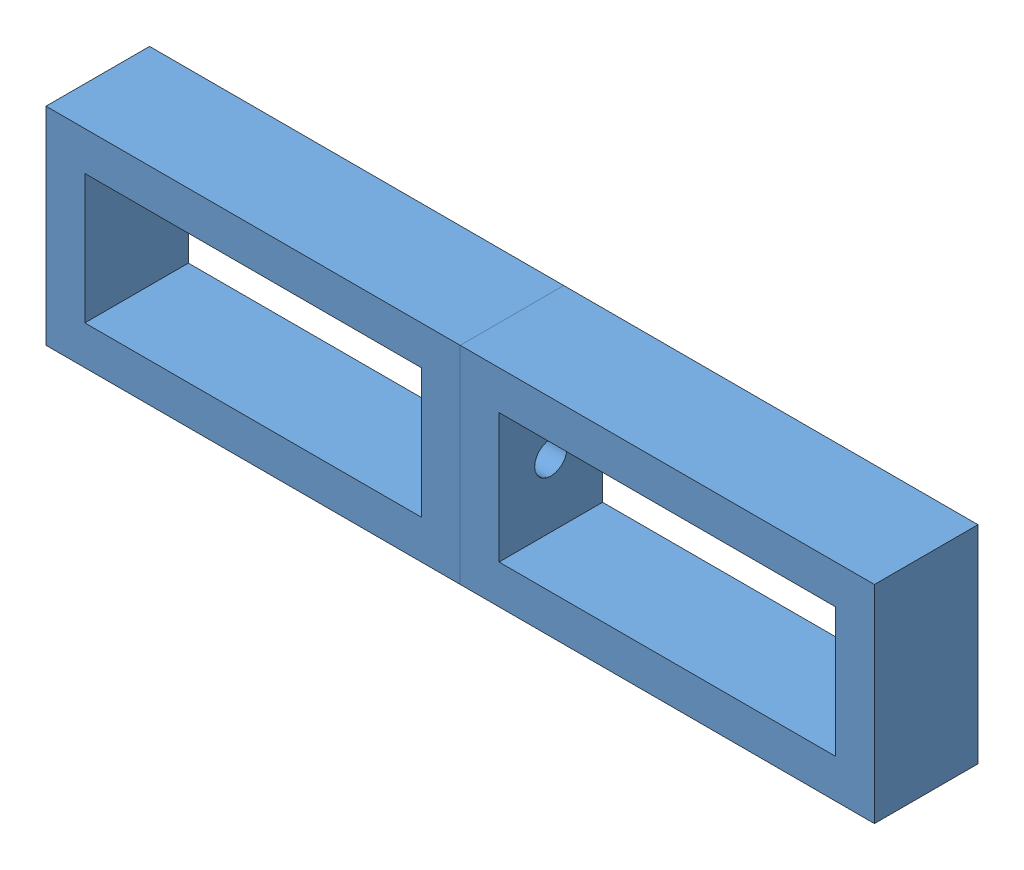
SolidWorks assembly Bolts Assem, configuration Default. Lengths in mm.
Overall size (406.4 101.6 50.8).
2 component instances, 1 part files, 4 mates.
Components (placement in the parent):
- bc1-1: bc1 [Default] at origin size (203.2 101.6 50.8)
- bc1-2: bc1 [Default] at (0 0 50.8) x (-1 0 0) z (0 0 -1) size (203.2 101.6 50.8)
Mates (geometry in assembly coordinates):
- Coincident1: coordinate: point of bc1-1
- Coincident2: coincident aligned: plane of bc1-1 through (0 0 0) normal (0 0 1); plane of assembly through (0 0 0) normal (0 0 1)
- Concentric2: concentric anti-aligned: circle of bc1-1; circle of bc1-2
- Coincident10: coincident: point of bc1-1; point of bc1-2
